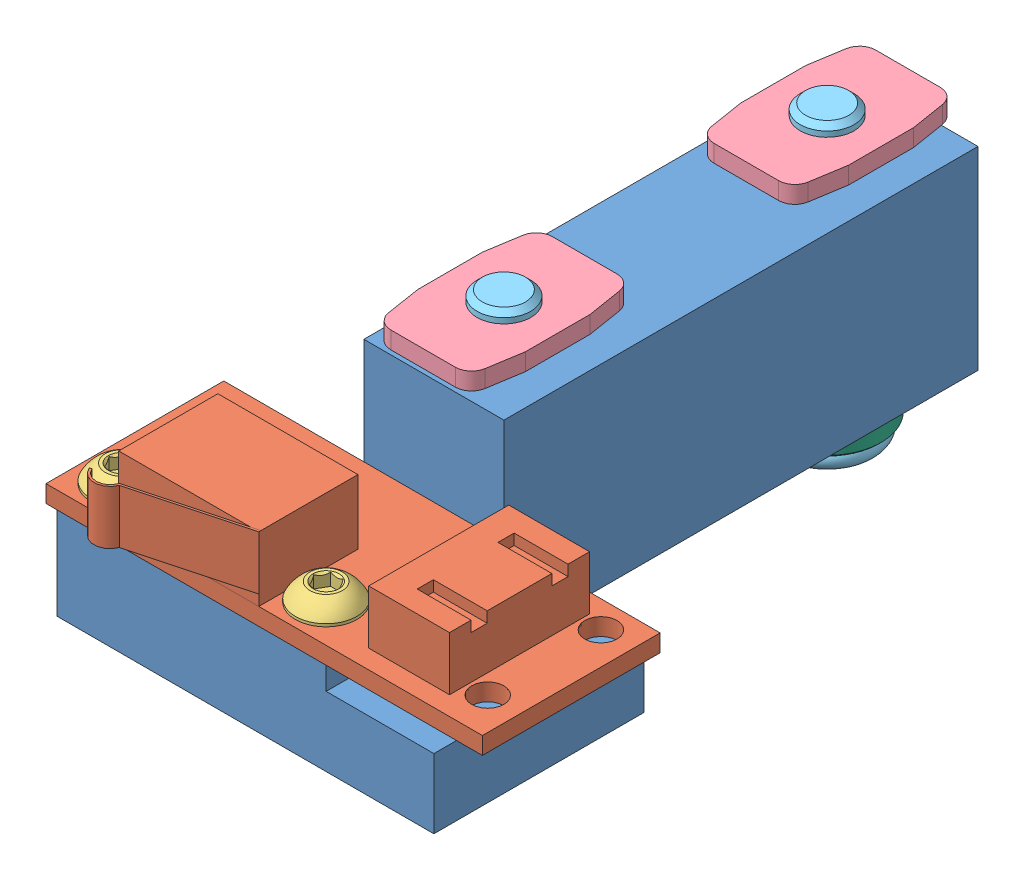
SolidWorks assembly X-Axis Endstop, configuration Default. Lengths in mm.
Overall size (40.5 26.62 66.47).
10 component instances, 6 part files, 20 mates.
Components (placement in the parent):
- XAxis Endstop Holder-1: XAxis Endstop Holder [Default] at (18.0974 23.5878 72.2541) size (35 18 62.5)
- RAMPSEndStop-1: RAMPSEndStop [Default] at (20.3474 32.6378 74.2541) x (-1 0 0) z (0 0 -1) size (40.5 7.6 19.97)
- Button Head Socket Cap Screw M3-1: Button Head Socket Cap Screw M3 [M3 x 10] at (22.5974 24.2378 79.0041) x (0 -1 0) z (0 0 1) size (11.72 5.7 5.7)
- Button Head Socket Cap Screw M3-2: Button Head Socket Cap Screw M3 [M3 x 10] at (3.5974 24.2378 79.0041) x (0 -1 0) z (0 0 1) size (11.72 5.7 5.7)
- Tee Nut-3: Tee Nut [Default] at (17.0974 44.5878 57.0041) x (0 0 -1) z (0 -1 0) size (15 10 3)
- Tee Nut-4: Tee Nut [Default] at (17.0974 44.5878 27.0041) x (0 0 -1) z (0 -1 0) size (15 10 3)
- Low Profile Screw M5-3: Low Profile Screw M5 [M5 x 25] at (17.0974 45.5878 27.0041) x (0 1 0) z (1 0 0) size (26.62 9 9)
- Low Profile Screw M5-4: Low Profile Screw M5 [M5 x 25] at (17.0974 45.5878 57.0041) x (0 1 0) z (1 0 0) size (26.62 9 9)
- Aluminum Spacer 3mm-3: Aluminum Spacer 3mm [Default] at (17.0974 23.5878 27.0041) x (1 0 0) z (0 -1 0) size (10 10 3)
- Aluminum Spacer 3mm-4: Aluminum Spacer 3mm [Default] at (17.0974 23.5878 57.0041) x (1 0 0) z (0 -1 0) size (10 10 3)
Mates (geometry in assembly coordinates):
- Coincident2: coincident anti-aligned: plane of XAxis Endstop Holder-1 through (18.0974 32.6378 72.2541) normal (0 1 0); plane of RAMPSEndStop-1 through (20.3474 32.6378 74.2541) normal (0 -1 0)
- Concentric1: concentric anti-aligned: cylinder of XAxis Endstop Holder-1 through (22.5974 23.5878 79.0041) axis (0 1 0) radius 1.4; cylinder of RAMPSEndStop-1 through (22.5974 34.2378 79.0041) axis (0 -1 0) radius 1.5
- Concentric2: concentric anti-aligned: cylinder of XAxis Endstop Holder-1 through (22.5974 23.5878 79.0041) axis (0 1 0) radius 1.4; cylinder of Button Head Socket Cap Screw M3-1 through (22.5974 34.2378 79.0041) axis (0 -1 0) radius 1.5
- Coincident3: coincident anti-aligned: plane of RAMPSEndStop-1 through (20.3474 34.2378 74.2541) normal (0 1 0); plane of Button Head Socket Cap Screw M3-1 through (25.4474 34.2378 79.0041) normal (0 -1 0)
- Concentric3: concentric anti-aligned: cylinder of XAxis Endstop Holder-1 through (3.5974 23.5878 79.0041) axis (0 1 0) radius 1.4; cylinder of Button Head Socket Cap Screw M3-2 through (3.5974 34.2378 79.0041) axis (0 -1 0) radius 1.5
- Coincident4: coincident anti-aligned: plane of RAMPSEndStop-1 through (20.3474 34.2378 74.2541) normal (0 1 0); plane of Button Head Socket Cap Screw M3-2 through (6.4474 34.2378 79.0041) normal (0 -1 0)
- Coincident15: coincident anti-aligned: plane of XAxis Endstop Holder-1 through (18.0974 23.5878 72.2541) normal (0 -1 0); plane of Aluminum Spacer 3mm-4 through (17.0974 23.5878 57.0041) normal (0 1 0)
- Concentric10: concentric aligned: cylinder of XAxis Endstop Holder-1 through (17.0974 23.5878 57.0041) axis (0 1 0) radius 3.5; cylinder of Aluminum Spacer 3mm-4 through (17.0974 20.5878 57.0041) axis (0 1 0) radius 2.55
- Coincident16: coincident anti-aligned: plane of XAxis Endstop Holder-1 through (18.0974 23.5878 72.2541) normal (0 -1 0); plane of Aluminum Spacer 3mm-3 through (17.0974 23.5878 27.0041) normal (0 1 0)
- Concentric11: concentric aligned: cylinder of XAxis Endstop Holder-1 through (17.0974 23.5878 27.0041) axis (0 1 0) radius 3.5; cylinder of Aluminum Spacer 3mm-3 through (17.0974 20.5878 27.0041) axis (0 1 0) radius 2.55
- Concentric12: concentric aligned: cylinder of XAxis Endstop Holder-1 through (17.0974 23.5878 57.0041) axis (0 1 0) radius 3.5; cylinder of Low Profile Screw M5-4 through (17.0974 20.5878 57.0041) axis (0 1 0) radius 2.5
- Coincident17: coincident anti-aligned: plane of Low Profile Screw M5-4 through (17.0974 20.5878 61.1656) normal (0 1 0); plane of Aluminum Spacer 3mm-4 through (17.0974 20.5878 57.0041) normal (0 -1 0)
- Concentric13: concentric aligned: cylinder of XAxis Endstop Holder-1 through (17.0974 23.5878 27.0041) axis (0 1 0) radius 3.5; cylinder of Low Profile Screw M5-3 through (17.0974 20.5878 27.0041) axis (0 1 0) radius 2.5
- Coincident18: coincident anti-aligned: plane of Low Profile Screw M5-3 through (17.0974 20.5878 31.1656) normal (0 1 0); plane of Aluminum Spacer 3mm-3 through (17.0974 20.5878 27.0041) normal (0 -1 0)
- Concentric14: concentric anti-aligned: cylinder of Tee Nut-4 through (17.0974 41.5878 27.0041) axis (0 -1 0) radius 2.1; cylinder of Low Profile Screw M5-3 through (17.0974 20.5878 27.0041) axis (0 1 0) radius 2.5
- Coincident19: coincident anti-aligned: plane of XAxis Endstop Holder-1 through (18.0974 41.5878 72.2541) normal (0 1 0); plane of Tee Nut-4 through (17.0974 41.5878 27.0041) normal (0 -1 0)
- Parallel4: parallel anti-aligned: plane of XAxis Endstop Holder-1 through (10.5974 41.5878 19.5041) normal (0 0 -1); plane of Tee Nut-4 through (14.0974 42.9878 34.5041) normal (0 0 1)
- Concentric15: concentric anti-aligned: cylinder of Tee Nut-3 through (17.0974 41.5878 57.0041) axis (0 -1 0) radius 2.1; cylinder of Low Profile Screw M5-4 through (17.0974 20.5878 57.0041) axis (0 1 0) radius 2.5
- Coincident21: coincident anti-aligned: plane of XAxis Endstop Holder-1 through (18.0974 41.5878 72.2541) normal (0 1 0); plane of Tee Nut-3 through (17.0974 41.5878 57.0041) normal (0 -1 0)
- Parallel5: parallel anti-aligned: plane of XAxis Endstop Holder-1 through (10.5974 41.5878 19.5041) normal (0 0 -1); plane of Tee Nut-3 through (14.0974 42.9878 64.5041) normal (0 0 1)
